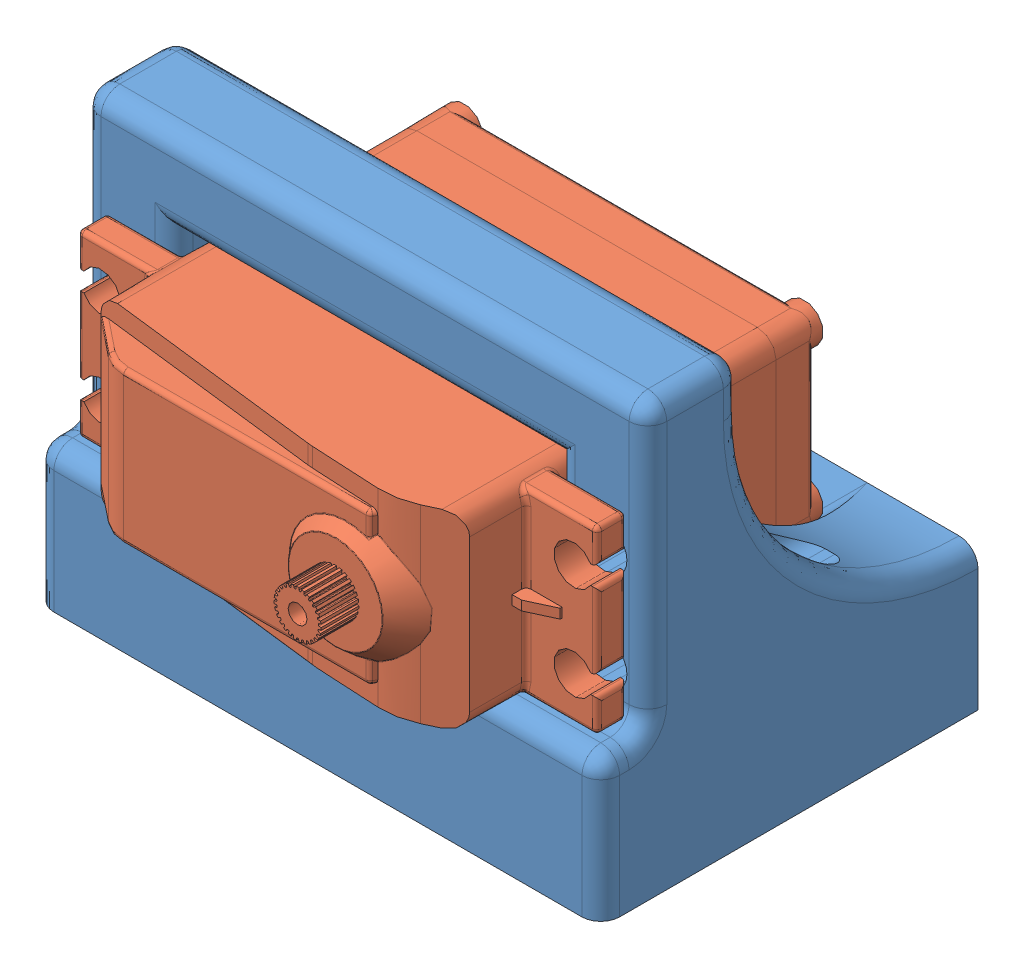
SolidWorks assembly Servo_Assembly_Reversed, configuration Default. Lengths in mm.
Overall size (60 45 52.3).
2 component instances, 2 part files, 3 mates.
Components (placement in the parent):
- 20kg_Servo_Holder-1: 20kg_Servo_Holder [Default] at origin size (60 45 40)
- Servo 20kg-1: Servo 20kg [Default] at (30.2 15.05 -33.35) x (1 0 0) z (0 -1 0) size (55.1 45.65 20.12)
Mates (geometry in assembly coordinates):
- Coincident1: coincident anti-aligned: plane of 20kg_Servo_Holder-1 through (0 5 0) normal (0 1 0); plane of Servo 20kg-1 through (50.25 5 7.15) normal (0 -1 0)
- Coincident2: coincident anti-aligned: plane of 20kg_Servo_Holder-1 through (50.25 35 -5) normal (-1 0 0); plane of Servo 20kg-1 through (50.25 5 7.15) normal (1 0 0)
- Coincident3: coincident anti-aligned: plane of 20kg_Servo_Holder-1 through (0 35 -5) normal (0 0 1); plane of Servo 20kg-1 through (5.15 10.05 -5) normal (0 0 -1)
